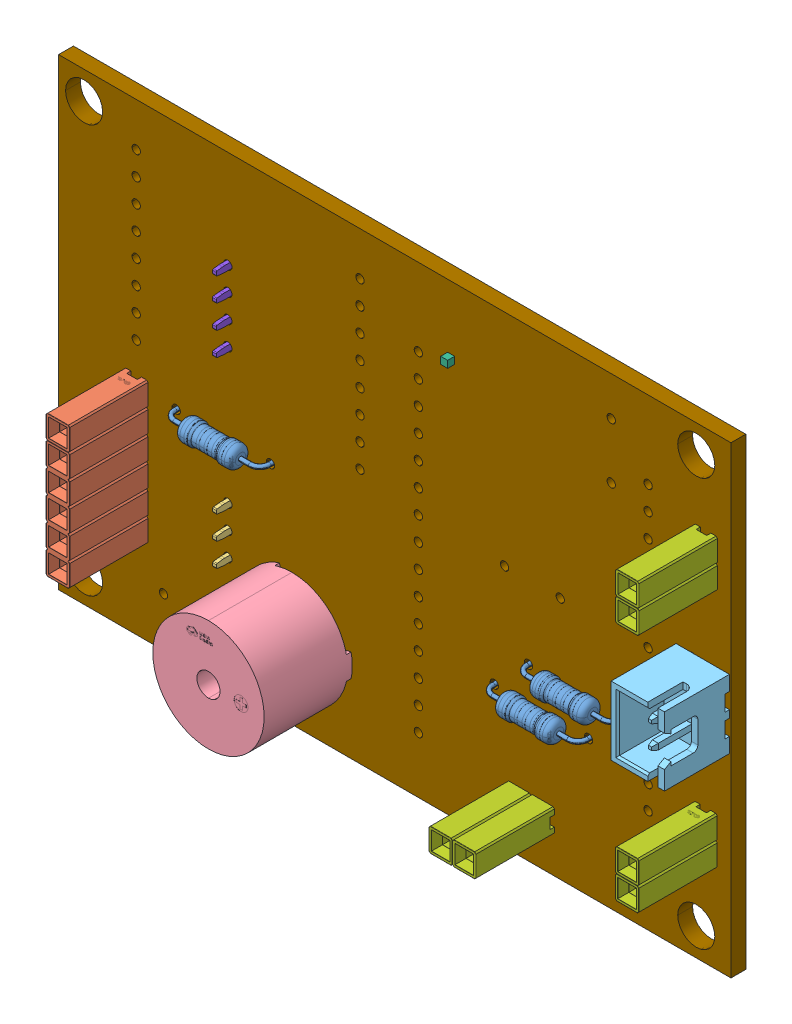
SolidWorks assembly 3D_PCB_Fire_Alarm_Final_PCB-copy_2025-10-18_2025-10-18, configuration Default. Lengths in mm.
Overall size (72.72 51.79 19.56).
26 component instances, 9 part files, 0 mates.
Components (placement in the parent):
- 3D_PCB_Fire_Alarm_Final_PCB-copy_2025-10-18_2025-10-18.step-1: 3D_PCB_Fire_Alarm_Final_PCB-copy_2025-10-18_2025-10-18.step [Default] at origin size (72.72 51.79 19.56)
  - 220~R_AXIAL-0.4~R_AXIAL-0.4~x08L.step-1: 220~R_AXIAL-0.4~R_AXIAL-0.4~x08L.step [Default] at (54.9911 -31.6231 1.6) size (10.6 2.32 5.8)
    - R_AXIAL-0.4~R_AXIAL-0.4~x08L.step-1: R_AXIAL-0.4~R_AXIAL-0.4~x08L.step [Default] at origin size (10.6 2.32 5.8)
  - 220~R_AXIAL-0.4~R_AXIAL-0.4~x08L.step-2: 220~R_AXIAL-0.4~R_AXIAL-0.4~x08L.step [Default] at (51.3081 -35.3061 1.6) x (-1 0 0) z (0 0 1) size (10.6 2.32 5.8)
    - R_AXIAL-0.4~R_AXIAL-0.4~x08L.step-1: R_AXIAL-0.4~R_AXIAL-0.4~x08L.step [Default] at origin size (10.6 2.32 5.8)
  - 220~R_AXIAL-0.4~R_AXIAL-0.4~x08L.step-3: 220~R_AXIAL-0.4~R_AXIAL-0.4~x08L.step [Default] at (17.018 -26.7971 1.6) x (-1 0 0) z (0 0 1) size (10.6 2.32 5.8)
    - R_AXIAL-0.4~R_AXIAL-0.4~x08L.step-1: R_AXIAL-0.4~R_AXIAL-0.4~x08L.step [Default] at origin size (10.6 2.32 5.8)
  - DUSTSSENSOR~HDR-F-2.54_1X6~HDR-F-2.54_1x6~x08L.step-1: DUSTSSENSOR~HDR-F-2.54_1X6~HDR-F-2.54_1x6~x08L.step [Default] at (7.62 -34.5441 1.6) x (0 1 0) z (0 0 1) size (15.24 2.54 11.5)
    - HDR-F-2.54_1X6~HDR-F-2.54_1x6~x08L.step-1: HDR-F-2.54_1X6~HDR-F-2.54_1x6~x08L.step [Default] at origin size (15.24 2.54 11.5)
  - DHT1~HDR-F-2.54_1X3~HDR-F-2.54_1x3~x08L.step-1: DHT1~HDR-F-2.54_1X3~HDR-F-2.54_1x3~x08L.step [Default] at (17.5 -35.3061 0) x (0 1 0) z (0 0 -1) size (7.62 2.54 11.5)
    - HDR-F-2.54_1X3~HDR-F-2.54_1x3~x08L.step-1: HDR-F-2.54_1X3~HDR-F-2.54_1x3~x08L.step [Default] at origin size (7.62 2.54 11.5)
  - BUZZER~BUZ-TH_BD12.0-P7.60-D0.6-FD~BUZ-TH_D12.0-H9.5-P7.60~x08L.step-1: BUZZER~BUZ-TH_BD12.0-P7.60-D0.6-FD~BUZ-TH_D12.0-H9.5-P7.60~x08L.step [Default] at (24.892 -41.2751 1.6) x (-1 0 0) z (0 0 1) size (12 12 14.01)
    - BUZ-TH_BD12.0-P7.60-D0.6-FD~BUZ-TH_D12.0-H9.5-P7.60~x08L.step-1: BUZ-TH_BD12.0-P7.60-D0.6-FD~BUZ-TH_D12.0-H9.5-P7.60~x08L.step [Default] at origin size (12 12 14.01)
  - MAINSW~HDR-F-2.54_1X2~CONN-TH_2P-P2.50_JST_B2B-XH-A-M_C2858045~x08L.step-1: MAINSW~HDR-F-2.54_1X2~CONN-TH_2P-P2.50_JST_B2B-XH-A-M_C2858045~x08L.step [Default] at (69 -25.0191 1.6) x (0 -1 0) z (0 0 1) size (7.4 5.75 10.4)
    - HDR-F-2.54_1X2~CONN-TH_2P-P2.50_JST_B2B-XH-A-M_C2858045~x08L.step-1: HDR-F-2.54_1X2~CONN-TH_2P-P2.50_JST_B2B-XH-A-M_C2858045~x08L.step [Default] at origin size (7.4 5.75 10.4)
  - ESP32~ESP32-DEVKITV1_ESP32-DEVKITV1~esp32devkit30pin~x08L.step-1: ESP32~ESP32-DEVKITV1_ESP32-DEVKITV1~esp32devkit30pin~x08L.step [Default] at (43.3071 -26.7971 1.6) x (-1 0 0) z (0 0 1) size (0.76 0.76 0.76)
    - ESP32-DEVKITV1_ESP32-DEVKITV1~esp32devkit30pin~x08L.step-1: ESP32-DEVKITV1_ESP32-DEVKITV1~esp32devkit30pin~x08L.step [Default] at origin size (0.76 0.76 0.76)
  - -BATTERY+~HDR-F-2.54_1X2~HDR-F-2.54_1x2~x08L.step-1: -BATTERY+~HDR-F-2.54_1X2~HDR-F-2.54_1x2~x08L.step [Default] at (68.9992 -12.065 1.6) x (0 -1 0) z (0 0 1) size (5.08 2.54 11.5)
    - HDR-F-2.54_1X2~HDR-F-2.54_1x2~x08L.step-1: HDR-F-2.54_1X2~HDR-F-2.54_1x2~x08L.step [Default] at origin size (5.08 2.54 11.5)
  - -BATTERY+~HDR-F-2.54_1X2~HDR-F-2.54_1x2~x08L.step-2: -BATTERY+~HDR-F-2.54_1X2~HDR-F-2.54_1x2~x08L.step [Default] at (68.9992 -37.9731 1.6) x (0 1 0) z (0 0 1) size (5.08 2.54 11.5)
    - HDR-F-2.54_1X2~HDR-F-2.54_1x2~x08L.step-1: HDR-F-2.54_1X2~HDR-F-2.54_1x2~x08L.step [Default] at origin size (5.08 2.54 11.5)
  - -BATTERY+~HDR-F-2.54_1X2~HDR-F-2.54_1x2~x08L.step-3: -BATTERY+~HDR-F-2.54_1X2~HDR-F-2.54_1x2~x08L.step [Default] at (50.1651 -44.8311 1.6) x (-1 0 0) z (0 0 1) size (5.08 2.54 11.5)
    - HDR-F-2.54_1X2~HDR-F-2.54_1x2~x08L.step-1: HDR-F-2.54_1X2~HDR-F-2.54_1x2~x08L.step [Default] at origin size (5.08 2.54 11.5)
  - MQ2~HDR-F-2.54_1X4~HDR-F-2.54_1x4~x08L.step-1: MQ2~HDR-F-2.54_1X4~HDR-F-2.54_1x4~x08L.step [Default] at (17.5 -14.351 0) x (0 -1 0) z (0 0 -1) size (10.16 2.54 11.5)
    - HDR-F-2.54_1X4~HDR-F-2.54_1x4~x08L.step-1: HDR-F-2.54_1X4~HDR-F-2.54_1x4~x08L.step [Default] at origin size (10.16 2.54 11.5)
  - Board~x08L.step-1: Board~x08L.step [Default] at origin size (72.49 49.97 1.6)
